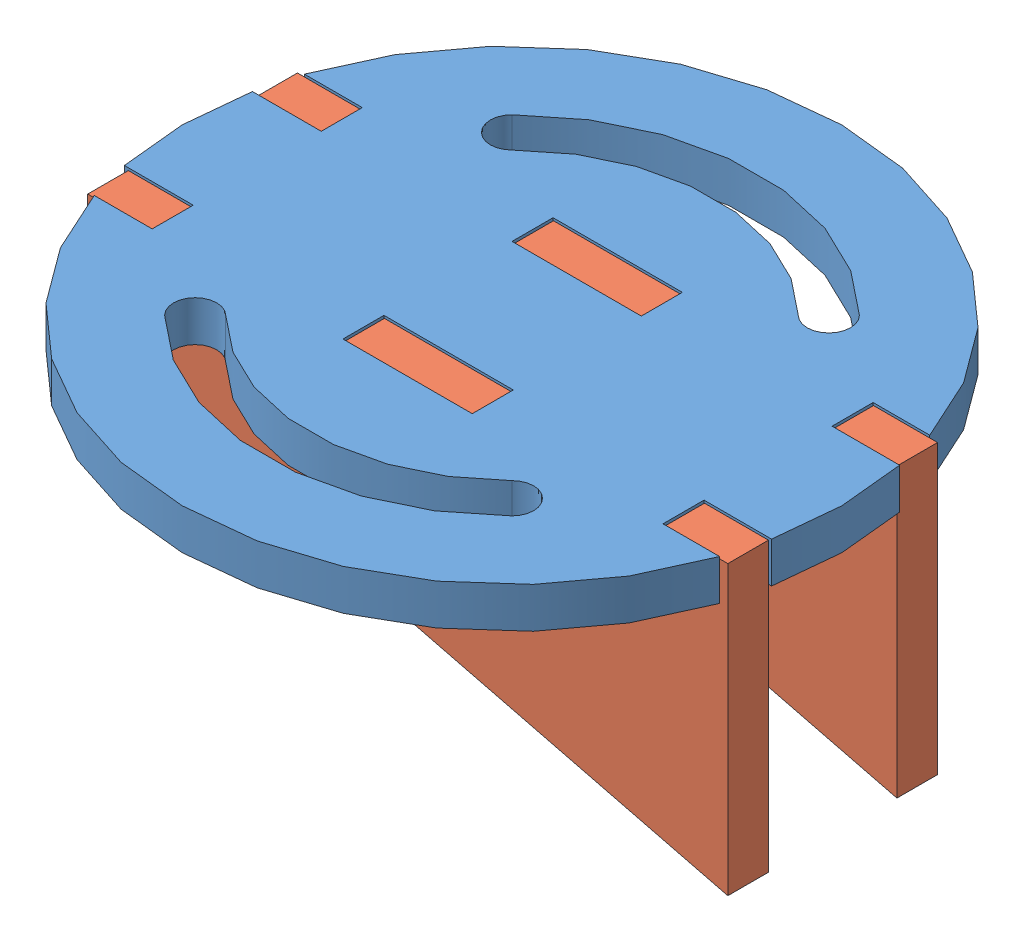
SolidWorks assembly Assem1, configuration Default. Lengths in mm.
Overall size (103.06 45.28 103.06).
3 component instances, 2 part files, 6 mates.
Components (placement in the parent):
- circle_mount-1: circle_mount [Default] at (23.8067 43.6843 91.5495) size (103.06 6.35 103.06)
- side_mount_flange-1: side_mount_flange [Default] at (-26.0933 49.6843 107.9312) x (1 0 0) z (0 1 0) size (100 6.35 44.93)
- side_mount_flange-2: side_mount_flange [Default] at (-26.0933 49.6843 81.5177) x (1 0 0) z (0 1 0) size (100 6.35 44.93)
Mates (geometry in assembly coordinates):
- Width1: width: plane of side_mount_flange-2 through (-26.0933 25.2076 75.1677) normal (0 0 -1); plane of side_mount_flange-2 through (-26.0933 25.2076 81.5177) normal (0 0 1); plane of circle_mount-1 through (23.8067 50.0343 75.136) normal (0 0 1); plane of circle_mount-1 through (23.8067 50.0343 81.5495) normal (0 0 -1)
- Width2: width: plane of side_mount_flange-2 through (33.9067 25.2076 75.1677) normal (1 0 0); plane of side_mount_flange-2 through (13.9067 19.2076 75.1677) normal (-1 0 0); plane of circle_mount-1 through (34.0067 50.0343 91.5495) normal (-1 0 0); plane of circle_mount-1 through (13.8067 50.0343 91.5495) normal (1 0 0)
- Width4: width anti-aligned: plane of side_mount_flange-1 through (-26.0933 49.6843 107.9312) normal (0 0 1); plane of side_mount_flange-1 through (-26.0933 49.6843 101.5812) normal (0 0 -1); plane of circle_mount-1 through (23.8067 50.0343 107.963) normal (0 0 -1); plane of circle_mount-1 through (23.8067 50.0343 101.5495) normal (0 0 1)
- Width5: width anti-aligned: plane of side_mount_flange-1 through (33.9067 49.6843 101.5812) normal (1 0 0); plane of side_mount_flange-1 through (13.9067 43.6843 101.5812) normal (-1 0 0); plane of circle_mount-1 through (34.0067 50.0343 91.5495) normal (-1 0 0); plane of circle_mount-1 through (13.8067 50.0343 91.5495) normal (1 0 0)
- Coincident3: coincident anti-aligned: plane of circle_mount-1 through (23.8067 43.6843 91.5495) normal (0 -1 0); plane of side_mount_flange-1 through (-16.0933 43.6843 101.5812) normal (0 1 0)
- Coincident4: coincident anti-aligned: plane of circle_mount-1 through (23.8067 43.6843 91.5495) normal (0 -1 0); plane of side_mount_flange-2 through (-16.0933 43.6843 75.1677) normal (0 1 0)
